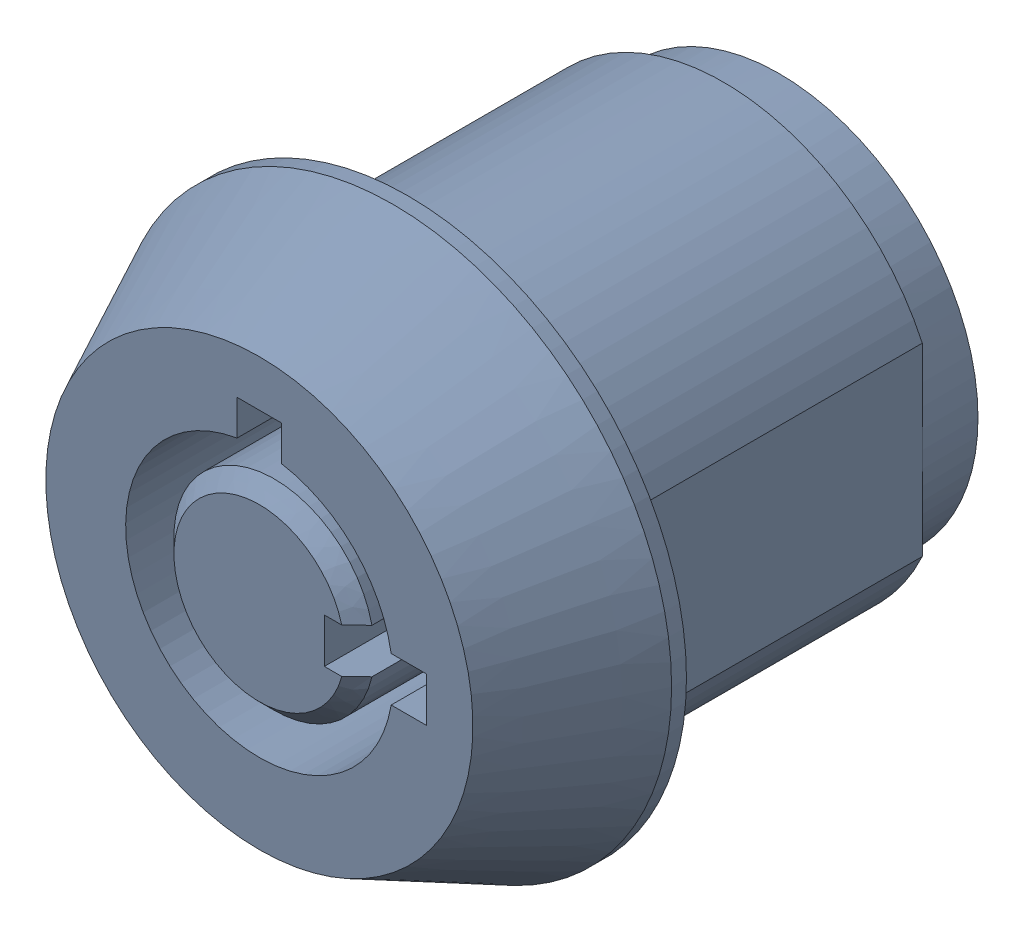
SolidWorks assembly Lock Assy(Default)-1-2, configuration Default. Lengths in mm.
Overall size (15 15 15.5).
2 component instances, 1 part files, 0 mates.
Components (placement in the parent):
- Lock - 10220022001-1-2-1: Lock - 10220022001-1-2 [Default] at (0 0 7.5) x (-1 0 0) z (0 0 -1) size (15 15 15.5)
  - Lock Body - 10220022001-2-1: Lock Body - 10220022001-2 [Default] x (-1 0 0) z (0 0 1) size (15 15 15.5)
